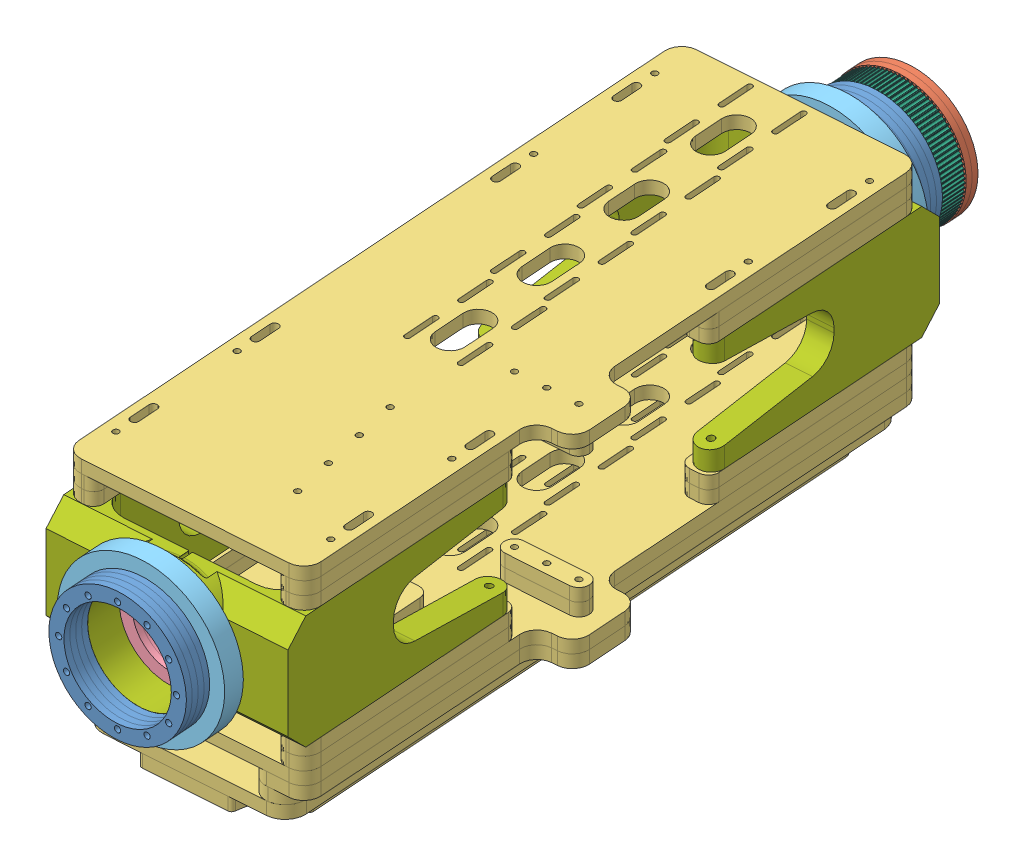
SolidWorks assembly teststand_TR1, configuration Default. Lengths in mm.
Overall size (155.9 123.66 428.09).
34 component instances, 7 part files, 70 mates.
Components (placement in the parent):
- teststand_TR1_TS_4-1: teststand_TR1_TS_4 [Default] at (-288.6237 -19.05 470.607) x (0.997521 0 -0.070363) z (0.070363 0 0.997521) size (64 64 3.17)
- teststand_TR1_carbon_tube_spacerbolt-1: teststand_TR1_carbon_tube_spacerbolt [Default] at (-352.7172 -19.05 59.3876) x (-0.997521 0 0.070363) z (-0.070363 0 -0.997521) size (64 64 3.17)
- teststand_TR1_plate-1: teststand_TR1_plate [Default] at (-320.0002 -94.6 274.4987) x (0.997521 0 -0.070363) z (0.070363 0 0.997521) size (131.35 6.35 330)
- teststand_TR1_carbon_tube_spacer-1: teststand_TR1_carbon_tube_spacer [Default] at (-308.1542 -47.3 442.4364) x (0.070363 0 0.997521) z (-0.997521 0 0.070363) size (3.17 50 50)
- teststand_TR1_Bearing-1: teststand_TR1_Bearing [Default] at (-307.426 -47.3 452.7608) x (0.997521 0 -0.070363) z (0.070363 0 0.997521) size (78 78 10)
- teststand_TR1_SDP_a_6a51m100nf0908-1: teststand_TR1_SDP_a_6a51m100nf0908 [Default] at (-335.2746 -47.3 57.9568) x (-0.997521 0 0.070363) z (-0.070363 0 -0.997521) size (63.18 63.18 12.7)
- teststand_TR1_plate-2: teststand_TR1_plate [steel] at (-320.0002 -113.65 274.4987) x (0.997521 0 -0.070363) z (0.070363 0 0.997521) size (95.7 6.35 330)
- teststand_TR1_plate-3: teststand_TR1_plate [steel21] at (-320.0002 -113.65 274.4987) x (-0.997521 0 0.070363) z (0.070363 0 0.997521) size (85.7 6.35 310)
- teststand_TR1_plate-4: teststand_TR1_plate [between] at (-320.0002 -100.95 274.4987) x (0.997521 0 -0.070363) z (0.070363 0 0.997521) size (131.35 6.35 330)
- teststand_TR1_plate-5: teststand_TR1_plate [spacer] at (-320.0002 -81.9 274.4987) x (0.997521 0 -0.070363) z (0.070363 0 0.997521) size (123.2 6.35 330)
- teststand_TR1_plate-6: teststand_TR1_plate [beetween2] at (-320.0002 -100.95 274.4987) x (-0.997521 0 0.070363) z (0.070363 0 0.997521) size (95.7 6.35 329.99)
- teststand_TR1_TS_2-1: teststand_TR1_TS_2 [Default] at (-337.8435 -75.55 270.2487) x (0.997521 0 -0.070363) z (0 1 0) size (112.7 135.35 64)
- teststand_TR1_plate-7: teststand_TR1_plate [spacer] at (-320.0002 -19.05 274.4987) x (0.997521 0 -0.070363) z (0.070363 0 0.997521) size (123.2 6.35 330)
- teststand_TR1_plate-8: teststand_TR1_plate [Default] at (-320.0002 -6.35 274.4987) x (0.997521 0 -0.070363) z (0.070363 0 0.997521) size (131.35 6.35 330)
- teststand_TR1_plate-9: teststand_TR1_plate [spacer] at (-320.0002 -12.7 274.4987) x (0.997521 0 -0.070363) z (0.070363 0 0.997521) size (123.2 6.35 330)
- teststand_TR1_plate-10: teststand_TR1_plate [spacer] at (-320.0002 -88.25 274.4987) x (0.997521 0 -0.070363) z (0.070363 0 0.997521) size (123.2 6.35 330)
- teststand_TR1_carbon_tube_spacer-2: teststand_TR1_carbon_tube_spacer [Default] at (-308.3777 -47.3 439.2693) x (0.070363 0 0.997521) z (-0.997521 0 0.070363) size (3.17 50 50)
- teststand_TR1_carbon_tube_spacer-3: teststand_TR1_carbon_tube_spacer [Default] at (-308.6011 -47.3 436.1022) x (0.070363 0 0.997521) z (-0.997521 0 0.070363) size (3.17 50 50)
- teststand_TR1_carbon_tube_spacer-4: teststand_TR1_carbon_tube_spacer [Default] at (-335.0512 -47.3 61.1239) x (-0.070363 0 -0.997521) z (-0.917892 -0.391513 0.064746) size (3.17 50 50)
- teststand_TR1_carbon_tube_spacer-5: teststand_TR1_carbon_tube_spacer [Default] at (-334.8278 -47.3 64.291) x (-0.070363 0 -0.997521) z (-0.917892 -0.391513 0.064746) size (3.17 50 50)
- teststand_TR1_carbon_tube_spacer-6: teststand_TR1_carbon_tube_spacer [Default] at (-334.6044 -47.3 67.4581) x (-0.070363 0 -0.997521) z (-0.917892 -0.391513 0.064746) size (3.17 50 50)
- teststand_TR1_carbon_tube_spacer-7: teststand_TR1_carbon_tube_spacer [Default] at (-334.381 -47.3 70.6253) x (-0.070363 0 -0.997521) z (-0.917892 -0.391513 0.064746) size (3.17 50 50)
- teststand_TR1_carbon_tube_spacer-8: teststand_TR1_carbon_tube_spacer [Default] at (-334.1576 -47.3 73.7924) x (-0.070363 0 -0.997521) z (-0.917892 -0.391513 0.064746) size (3.17 50 50)
- teststand_TR1_carbon_tube_spacerbolt-2: teststand_TR1_carbon_tube_spacerbolt [Default] at (-352.9406 -19.05 56.2205) x (-0.997521 0 0.070363) z (-0.070363 0 -0.997521) size (64 64 3.17)
- teststand_TR1_Bearing-2: teststand_TR1_Bearing [Default] at (-332.5744 -47.3 96.2366) x (0.921439 0.383049 -0.064996) z (-0.070363 0 -0.997521) size (78 78 10)
- teststand_TR1_TS_4-2: teststand_TR1_TS_4 [Default] at (-350.7065 -19.05 87.8918) x (-0.997521 0 0.070363) z (-0.070363 0 -0.997521) size (64 64 3.17)
- teststand_TR1_TS_2-3: teststand_TR1_TS_2 [Default] at (-302.1569 -75.55 278.7487) x (-0.997521 0 0.070363) z (0 1 0) size (112.7 135.35 64)
- teststand_TR1_TS_4-6: teststand_TR1_TS_4 [Default] at (-288.8471 -19.05 467.4399) x (0.997521 0 -0.070363) z (0.070363 0 0.997521) size (64 64 3.17)
- teststand_TR1_TS_4-7: teststand_TR1_TS_4 [Default] at (-289.0705 -19.05 464.2728) x (0.997521 0 -0.070363) z (0.070363 0 0.997521) size (64 64 3.17)
- teststand_TR1_TS_4-8: teststand_TR1_TS_4 [Default] at (-289.2939 -19.05 461.1056) x (0.997521 0 -0.070363) z (0.070363 0 0.997521) size (64 64 3.17)
- teststand_TR1_TS_4-9: teststand_TR1_TS_4 [Default] at (-350.93 -19.05 84.7247) x (-0.997521 0 0.070363) z (-0.070363 0 -0.997521) size (64 64 3.17)
- teststand_TR1_TS_4-10: teststand_TR1_TS_4 [Default] at (-351.1534 -19.05 81.5575) x (-0.997521 0 0.070363) z (-0.070363 0 -0.997521) size (64 64 3.17)
- teststand_TR1_TS_4-11: teststand_TR1_TS_4 [Default] at (-351.3768 -19.05 78.3904) x (-0.997521 0 0.070363) z (-0.070363 0 -0.997521) size (64 64 3.17)
- teststand_TR1_TS_4-12: teststand_TR1_TS_4 [Default] at (-351.6002 -19.05 75.2233) x (-0.997521 0 0.070363) z (-0.070363 0 -0.997521) size (64 64 3.17)
Mates (geometry in assembly coordinates):
- Coincident13: coincident: plane of teststand_TR1_plate-1 through (-320.0002 -88.25 274.4987) normal (0 1 0); plane of teststand_TR1_plate-10 through (-320.0002 -88.25 274.4987) normal (0 -1 0)
- Concentric3: concentric: cylinder of teststand_TR1_plate-1 through (-259.9563 -125.08 415.1274) axis (0 1 0) radius 1.5; cylinder of teststand_TR1_plate-10 through (-259.9563 -118.73 415.1274) axis (0 1 0) radius 1.5
- Concentric4: concentric: cylinder of teststand_TR1_plate-1 through (-359.7085 -125.08 422.1637) axis (0 1 0) radius 1.5; cylinder of teststand_TR1_plate-10 through (-359.7085 -118.73 422.1637) axis (0 1 0) radius 1.5
- Coincident17: coincident: plane of teststand_TR1_plate-1 through (-320.0002 -94.6 274.4987) normal (0 -1 0); plane of teststand_TR1_plate-4 through (-320.0002 -94.6 274.4987) normal (0 1 0)
- Concentric7: concentric: cylinder of teststand_TR1_plate-4 through (-280.2919 -131.43 126.8337) axis (0 1 0) radius 1.5; cylinder of teststand_TR1_plate-1 through (-280.2919 -125.08 126.8337) axis (0 1 0) radius 1.5
- Concentric8: concentric: cylinder of teststand_TR1_plate-4 through (-380.0441 -131.43 133.87) axis (0 1 0) radius 1.5; cylinder of teststand_TR1_plate-1 through (-380.0441 -125.08 133.87) axis (0 1 0) radius 1.5
- Coincident12: coincident: plane of teststand_TR1_plate-2 through (-320.0002 -113.65 274.4987) normal (0 -1 0); plane of teststand_TR1_plate-3 through (-320.0002 -113.65 274.4987) normal (0 1 0)
- Concentric1: concentric: cylinder of teststand_TR1_plate-2 through (-309.7976 -107.3 419.1393) axis (0 1 0) radius 1.1303; cylinder of teststand_TR1_plate-3 through (-309.7976 -120 419.1393) axis (0 -1 0) radius 1.1303
- Concentric2: concentric: cylinder of teststand_TR1_plate-2 through (-315.4266 -107.3 339.3376) axis (0 1 0) radius 1.1303; cylinder of teststand_TR1_plate-3 through (-315.4266 -120 339.3376) axis (0 -1 0) radius 1.1303
- Coincident18: coincident: plane of teststand_TR1_plate-2 through (-320.0002 -107.3 274.4987) normal (0 1 0); plane of teststand_TR1_plate-6 through (-320.0002 -107.3 274.4987) normal (0 -1 0)
- Concentric9: concentric: cylinder of teststand_TR1_plate-2 through (-346.8501 -107.3 431.7778) axis (0 1 0) radius 1.8986; cylinder of teststand_TR1_plate-6 through (-346.8501 -107.3 431.7778) axis (0 -1 0) radius 1.8986
- Concentric22: concentric: cylinder of teststand_TR1_plate-2 through (-368.6627 -107.3 122.5461) axis (0 1 0) radius 1.8986; cylinder of teststand_TR1_plate-6 through (-368.6627 -107.3 122.5461) axis (0 -1 0) radius 1.8986
- Concentric10: concentric: cylinder of teststand_TR1_plate-4 through (-346.8501 -94.6 431.7778) axis (0 1 0) radius 2.5527; cylinder of teststand_TR1_plate-6 through (-346.8501 -107.3 431.7778) axis (0 -1 0) radius 1.8986
- Concentric11: concentric: cylinder of teststand_TR1_plate-4 through (-271.3378 -94.6 426.4513) axis (0 1 0) radius 2.5527; cylinder of teststand_TR1_plate-6 through (-271.3378 -107.3 426.4513) axis (0 -1 0) radius 1.8986
- Coincident19: coincident: plane of teststand_TR1_plate-4 through (-320.0002 -100.95 274.4987) normal (0 -1 0); plane of teststand_TR1_plate-6 through (-320.0002 -100.95 274.4987) normal (0 1 0)
- Coincident14: coincident: plane of teststand_TR1_plate-10 through (-320.0002 -81.9 274.4987) normal (0 1 0); plane of teststand_TR1_plate-5 through (-320.0002 -81.9 274.4987) normal (0 -1 0)
- Concentric5: concentric: cylinder of teststand_TR1_plate-10 through (-259.9563 -118.73 415.1274) axis (0 1 0) radius 1.5; cylinder of teststand_TR1_plate-5 through (-259.9563 -112.38 415.1274) axis (0 1 0) radius 1.5
- Concentric6: concentric: cylinder of teststand_TR1_plate-10 through (-359.7085 -118.73 422.1637) axis (0 1 0) radius 1.5; cylinder of teststand_TR1_plate-5 through (-359.7085 -112.38 422.1637) axis (0 1 0) radius 1.5
- Coincident26: coincident: plane of teststand_TR1_plate-5 through (-320.0002 -75.55 274.4987) normal (0 1 0); plane of teststand_TR1_TS_2-1 through (-265.9372 -75.55 330.3381) normal (0 -1 0)
- Concentric28: concentric: cylinder of teststand_TR1_plate-5 through (-265.9372 -85.55 330.3381) axis (0 1 0) radius 2; cylinder of teststand_TR1_TS_2-1 through (-265.9372 90.5384 330.3381) axis (0 -1 0) radius 1.7272
- Concentric29: concentric: cylinder of teststand_TR1_plate-5 through (-365.6893 -85.55 337.3744) axis (0 1 0) radius 2; cylinder of teststand_TR1_TS_2-1 through (-365.6893 90.5384 337.3744) axis (0 -1 0) radius 1.7272
- Coincident28: coincident: plane of teststand_TR1_plate-7 through (-320.0002 -19.05 274.4987) normal (0 -1 0); plane of teststand_TR1_TS_2-1 through (-337.8435 -19.05 270.2487) normal (0 1 0)
- Concentric30: concentric: cylinder of teststand_TR1_plate-7 through (-265.9372 -22.7 330.3381) axis (0 1 0) radius 2; cylinder of teststand_TR1_TS_2-1 through (-265.9372 90.5384 330.3381) axis (0 -1 0) radius 1.7272
- Concentric31: concentric: cylinder of teststand_TR1_plate-7 through (-365.6893 -22.7 337.3744) axis (0 1 0) radius 2; cylinder of teststand_TR1_TS_2-1 through (-365.6893 90.5384 337.3744) axis (0 -1 0) radius 1.7272
- Concentric18: concentric: cylinder of teststand_TR1_plate-7 through (-259.9563 -49.53 415.1274) axis (0 1 0) radius 1.5; cylinder of teststand_TR1_plate-8 through (-259.9563 -36.83 415.1274) axis (0 1 0) radius 1.5
- Concentric19: concentric: cylinder of teststand_TR1_plate-7 through (-359.7085 -49.53 422.1637) axis (0 1 0) radius 1.5; cylinder of teststand_TR1_plate-8 through (-359.7085 -36.83 422.1637) axis (0 1 0) radius 1.5
- Concentric20: concentric: cylinder of teststand_TR1_plate-9 through (-359.7085 -43.18 422.1637) axis (0 1 0) radius 1.5; cylinder of teststand_TR1_plate-7 through (-359.7085 -49.53 422.1637) axis (0 1 0) radius 1.5
- Coincident24: coincident: plane of teststand_TR1_plate-9 through (-320.0002 -12.7 274.4987) normal (0 -1 0); plane of teststand_TR1_plate-7 through (-320.0002 -12.7 274.4987) normal (0 1 0)
- Concentric21: concentric: cylinder of teststand_TR1_plate-9 through (-259.9563 -43.18 415.1274) axis (0 1 0) radius 1.5; cylinder of teststand_TR1_plate-7 through (-259.9563 -49.53 415.1274) axis (0 1 0) radius 1.5
- Coincident27: coincident: plane of teststand_TR1_plate-9 through (-320.0002 -6.35 274.4987) normal (0 1 0); plane of teststand_TR1_plate-8 through (-320.0002 -6.35 274.4987) normal (0 -1 0)
- Coincident30: coincident: plane of teststand_TR1_plate-8 through (-320.0002 0 274.4987) normal (0 1 0); plane of assembly through (0 0 0) normal (0 1 0)
- Concentric32: concentric: cylinder of teststand_TR1_carbon_tube_spacer-1 through (-307.9308 -47.3 445.6036) axis (-0.070363 0 -0.997521) radius 25; cylinder of teststand_TR1_TS_2-1 through (-316.2601 -47.3 327.522) axis (0.070363 0 0.997521) radius 25
- Coincident32: coincident: plane of teststand_TR1_TS_2-1 through (-364.8114 94.3633 440.0671) normal (-0.070363 0 -0.997521); plane of teststand_TR1_carbon_tube_spacer-3 through (-308.6011 -47.3 436.1022) normal (-0.070363 0 -0.997521)
- Concentric33: concentric: cylinder of teststand_TR1_TS_4-1 through (-305.8428 -47.3 475.205) axis (-0.070363 0 -0.997521) radius 32; cylinder of teststand_TR1_TS_2-1 through (-306.7364 -47.3 462.5365) axis (-0.070363 0 -0.997521) radius 29.9
- Concentric34: concentric: cylinder of teststand_TR1_TS_4-1 through (-305.8428 -19.85 475.205) axis (-0.070363 0 -0.997521) radius 1.4732; cylinder of teststand_TR1_TS_2-1 through (-316.2601 -19.85 327.522) axis (0.070363 0 0.997521) radius 1.1303
- Concentric35: concentric: cylinder of teststand_TR1_SDP_a_6a51m100nf0908-1 through (-334.381 -47.3 70.6253) axis (-0.070363 0 -0.997521) radius 25; cylinder of teststand_TR1_TS_2-1 through (-316.2601 -47.3 327.522) axis (0.070363 0 0.997521) radius 25
- Concentric36: concentric: cylinder of teststand_TR1_TS_4-1 through (-305.8428 -19.85 475.205) axis (-0.070363 0 -0.997521) radius 1.4732; cylinder of teststand_TR1_SDP_a_6a51m100nf0908-1 through (-334.381 -19.85 70.6253) axis (-0.070363 0 -0.997521) radius 1.4732
- Coincident35: coincident: plane of teststand_TR1_SDP_a_6a51m100nf0908-1 through (-335.2746 -47.3 57.9568) normal (-0.070363 0 -0.997521); plane of teststand_TR1_carbon_tube_spacer-4 through (-335.2746 -47.3 57.9568) normal (-0.070363 0 -0.997521)
- Concentric37: concentric: cylinder of teststand_TR1_SDP_a_6a51m100nf0908-1 through (-334.381 -47.3 70.6253) axis (-0.070363 0 -0.997521) radius 25; cylinder of teststand_TR1_carbon_tube_spacer-4 through (-335.2746 -47.3 57.9568) axis (0.070363 0 0.997521) radius 25
- Concentric38: concentric: cylinder of teststand_TR1_carbon_tube_spacerbolt-1 through (-335.498 -47.3 54.7896) axis (0.070363 0 0.997521) radius 32; cylinder of teststand_TR1_TS_2-1 through (-306.7364 -47.3 462.5365) axis (-0.070363 0 -0.997521) radius 29.9
- Coincident36: coincident: plane of teststand_TR1_carbon_tube_spacerbolt-1 through (-335.2746 -47.3 57.9568) normal (0.070363 0 0.997521); plane of teststand_TR1_SDP_a_6a51m100nf0908-1 through (-335.2746 -47.3 57.9568) normal (-0.070363 0 -0.997521)
- Concentric39: concentric: cylinder of teststand_TR1_carbon_tube_spacerbolt-1 through (-335.498 -19.85 54.7896) axis (0.070363 0 0.997521) radius 1.4732; cylinder of teststand_TR1_SDP_a_6a51m100nf0908-1 through (-334.381 -19.85 70.6253) axis (-0.070363 0 -0.997521) radius 1.4732
- Coincident37: coincident: plane of teststand_TR1_Bearing-1 through (-307.426 -47.3 452.7608) normal (-0.070363 0 -0.997521); plane of teststand_TR1_TS_2-1 through (-307.426 -47.3 452.7608) normal (0.070363 0 0.997521)
- Concentric40: concentric: cylinder of teststand_TR1_Bearing-1 through (-306.7224 -47.3 462.736) axis (-0.070363 0 -0.997521) radius 30; cylinder of teststand_TR1_TS_2-1 through (-306.7364 -47.3 462.5365) axis (-0.070363 0 -0.997521) radius 29.9
- Concentric43: concentric: cylinder of teststand_TR1_Bearing-2 through (-333.2781 -47.3 86.2614) axis (0.070363 0 0.997521) radius 30; cylinder of teststand_TR1_TS_2-3 through (-333.264 -47.3 86.4609) axis (0.070363 0 0.997521) radius 29.9
- Concentric44: concentric: cylinder of teststand_TR1_TS_4-2 through (-333.4874 -19.85 83.2938) axis (0.070363 0 0.997521) radius 1.4732; cylinder of teststand_TR1_TS_2-3 through (-323.7404 -19.85 221.4755) axis (-0.070363 0 -0.997521) radius 1.1303
- Concentric45: concentric: cylinder of teststand_TR1_TS_4-2 through (-333.4874 -47.3 83.2938) axis (0.070363 0 0.997521) radius 32; cylinder of teststand_TR1_TS_2-3 through (-333.264 -47.3 86.4609) axis (0.070363 0 0.997521) radius 29.9
- Coincident39: coincident: plane of teststand_TR1_Bearing-2 through (-332.5744 -47.3 96.2366) normal (0.070363 0 0.997521); plane of teststand_TR1_TS_2-3 through (-332.5744 -47.3 96.2366) normal (-0.070363 0 -0.997521)
- Coincident40: coincident: plane of teststand_TR1_TS_4-2 through (-333.264 -47.3 86.4609) normal (0.070363 0 0.997521); plane of teststand_TR1_TS_2-3 through (-333.264 -47.3 86.4609) normal (-0.070363 0 -0.997521)
- Coincident43: coincident: plane of teststand_TR1_plate-7 through (-320.0002 -19.05 274.4987) normal (0 -1 0); plane of teststand_TR1_TS_2-3 through (-302.1569 -19.05 278.7487) normal (0 1 0)
- Concentric49: concentric: cylinder of teststand_TR1_plate-8 through (-374.0632 -10 218.6594) axis (0 1 0) radius 2; cylinder of teststand_TR1_TS_2-3 through (-374.0632 90.5384 218.6594) axis (0 -1 0) radius 1.7272
- Concentric50: concentric: cylinder of teststand_TR1_plate-8 through (-274.3111 -10 211.623) axis (0 1 0) radius 2; cylinder of teststand_TR1_TS_2-3 through (-274.3111 90.5384 211.623) axis (0 -1 0) radius 1.7272
- Width13: width: plane of teststand_TR1_plate-1 through (-320.0002 -88.25 274.4987) normal (0 1 0); plane of teststand_TR1_plate-8 through (-320.0002 -6.35 274.4987) normal (0 -1 0); plane of ? through (-335.9279 -6.35 150.3116) normal (0 1 0); plane of ? through (-335.9279 -88.25 150.3116) normal (0 -1 0)
- Parallel6: parallel: plane of teststand_TR1_TS_2-3 through (-380.3975 90.5384 219.1062) normal (-0.997521 0 0.070363); plane of ? through (-355.126 -14.35 126.8543) normal (-0.997521 0 0.070363)
- Concentric51: concentric: cylinder of ? through (-349.8393 -6.35 130.742) axis (0 -1 0) radius 1.905; cylinder of teststand_TR1_plate-8 through (-349.8393 -36.83 130.742) axis (0 1 0) radius 1.35
- Coincident44: coincident: plane of teststand_TR1_plate-8 through (-320.0002 0 274.4987) normal (0 1 0); plane of ? through (-335.9279 0 150.3116) normal (0 -1 0)
- Width14: width: plane of teststand_TR1_plate-1 through (-320.0002 -88.25 274.4987) normal (0 1 0); plane of teststand_TR1_plate-8 through (-320.0002 -6.35 274.4987) normal (0 -1 0); plane of ? through (-329.4172 -6.35 199.9766) normal (0 1 0); plane of ? through (-329.4172 -88.25 199.9766) normal (0 -1 0)
- Parallel7: parallel: plane of teststand_TR1_TS_2-3 through (-380.3975 90.5384 219.1062) normal (-0.997521 0 0.070363); plane of ? through (-351.1091 5 176.6952) normal (-0.997521 0 0.070363)
- Concentric52: concentric: cylinder of teststand_TR1_plate-8 through (-343.3286 -36.83 180.407) axis (0 1 0) radius 1.35; cylinder of ? through (-343.3286 -3 180.407) axis (0 1 0) radius 1.525
- Coincident46: coincident: plane of teststand_TR1_plate-8 through (-320.0002 0 274.4987) normal (0 1 0); plane of ? through (-329.4172 0 199.9766) normal (0 -1 0)
- Width15: width: plane of ? through (-322.9064 -6.35 249.6416) normal (0 1 0); plane of ? through (-322.9064 -88.25 249.6416) normal (0 -1 0); plane of teststand_TR1_plate-8 through (-320.0002 -6.35 274.4987) normal (0 -1 0); plane of teststand_TR1_plate-1 through (-320.0002 -88.25 274.4987) normal (0 1 0)
- Parallel8: parallel: plane of teststand_TR1_TS_2-3 through (-380.3975 90.5384 219.1062) normal (-0.997521 0 0.070363); plane of ? through (-344.5984 5 226.3602) normal (-0.997521 0 0.070363)
- Coincident48: coincident: plane of teststand_TR1_plate-8 through (-320.0002 0 274.4987) normal (0 1 0); plane of ? through (-322.9064 0 249.6416) normal (0 -1 0)
- Concentric53: concentric: cylinder of teststand_TR1_plate-8 through (-336.8179 -36.83 230.0719) axis (0 1 0) radius 1.35; cylinder of ? through (-336.8179 -3 230.0719) axis (0 1 0) radius 1.525
- Width16: width: plane of ? through (-316.3957 -6.35 299.3066) normal (0 1 0); plane of ? through (-316.3957 -88.25 299.3066) normal (0 -1 0); plane of teststand_TR1_plate-1 through (-320.0002 -88.25 274.4987) normal (0 1 0); plane of teststand_TR1_plate-8 through (-320.0002 -6.35 274.4987) normal (0 -1 0)
- Parallel9: parallel: plane of teststand_TR1_TS_2-3 through (-380.3975 90.5384 219.1062) normal (-0.997521 0 0.070363); plane of ? through (-338.0876 5 276.0252) normal (-0.997521 0 0.070363)
- Coincident49: coincident: plane of teststand_TR1_plate-8 through (-320.0002 0 274.4987) normal (0 1 0); plane of ? through (-316.3957 0 299.3066) normal (0 -1 0)
- Concentric54: concentric: cylinder of teststand_TR1_plate-8 through (-330.3072 -36.83 279.7369) axis (0 1 0) radius 1.35; cylinder of ? through (-330.3072 -3 279.7369) axis (0 1 0) radius 1.525
- Coincident51: coincident: plane of teststand_TR1_TS_2-1 through (-306.7364 -47.3 462.5365) normal (0.070363 0 0.997521); plane of teststand_TR1_TS_4-8 through (-306.7364 -47.3 462.5365) normal (-0.070363 0 -0.997521)
- Coincident53: coincident: plane of teststand_TR1_SDP_a_6a51m100nf0908-1 through (-334.381 -47.3 70.6253) normal (0.070363 0 0.997521); plane of teststand_TR1_TS_4-12 through (-334.381 -47.3 70.6253) normal (-0.070363 0 -0.997521)
